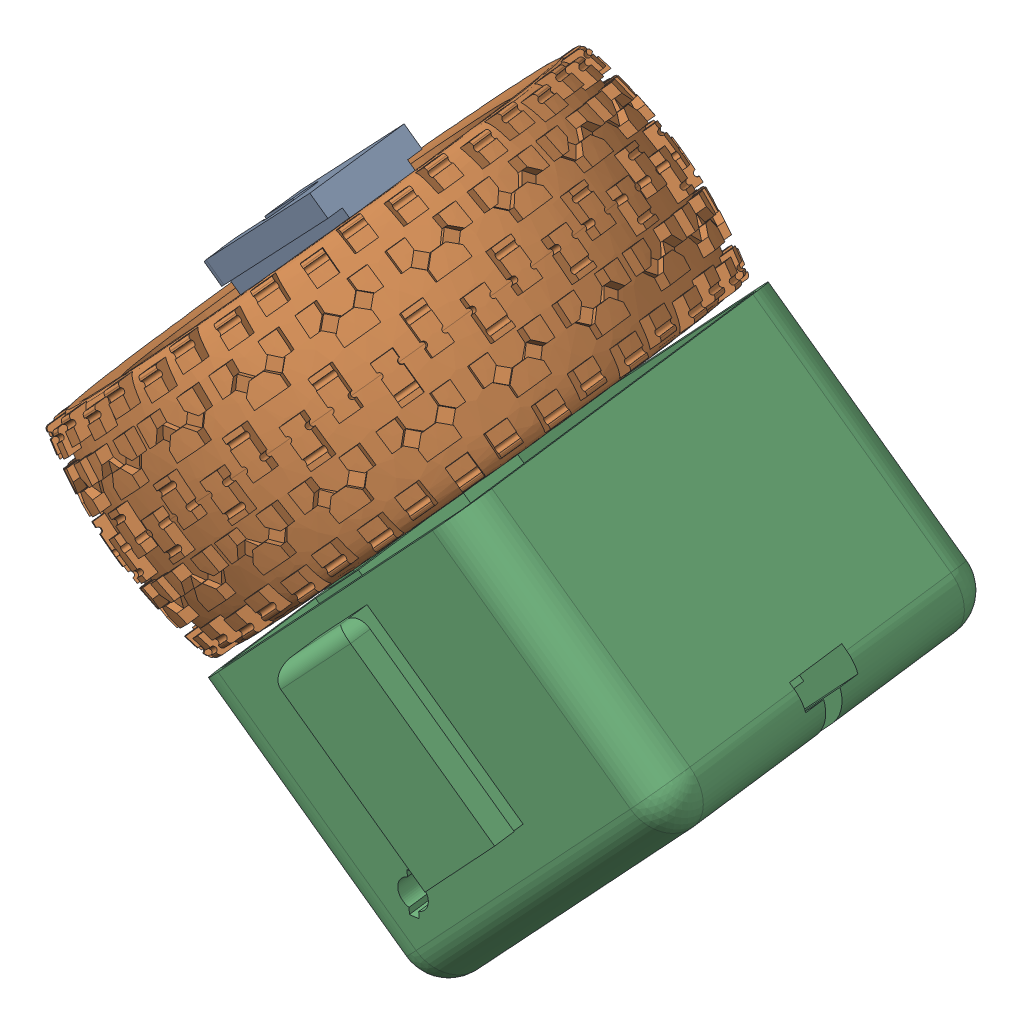
SolidWorks assembly wheel, configuration Default. Lengths in mm.
Overall size (95.78 91.17 74.59).
3 component instances, 3 part files, 4 mates.
Components (placement in the parent):
- top shell 5mm-1: top shell 5mm [Default] at (-4.933 7.7764 0.8566) x (0.34117 0.474596 -0.811395) z (-0.596658 -0.557668 -0.577066) size (46 23 46)
- wheel tred-2: wheel tred [Default] at (3.6765 -0.2954 -0.2446) x (0.726363 -0.681003 -0.092912) z (0.118622 -0.008941 0.992899) size (28.05 67.35 67.46)
- wheel_base-1: wheel_base [actuator bottom shell] at (42.2806 -36.4888 -5.1826) x (0.679481 0.731843 -0.052067) z (0.103455 -0.025312 0.994312) size (50 41.2 56)
Mates (geometry in assembly coordinates):
- Concentric2: concentric aligned: circle of top shell 5mm-1; circle of wheel tred-2
- Coincident2: coincident anti-aligned: plane of top shell 5mm-1 through (-4.933 7.7764 0.8566) normal (-0.896903 0.413893 0.155749); circle of wheel tred-2
- Concentric3: concentric aligned: cylinder of top shell 5mm-1 through (-4.933 7.7764 0.8566) axis (0.726363 -0.681003 -0.092912) radius 3.325
- Distance1: distance = 10 mm anti-aligned: plane of wheel_base-1 through (14.6788 -10.6107 -1.652) normal (-0.726363 0.681003 0.092912); plane of top shell 5mm-1 through (7.4152 -3.8006 -0.7229) normal (0.726363 -0.681003 -0.092912)
